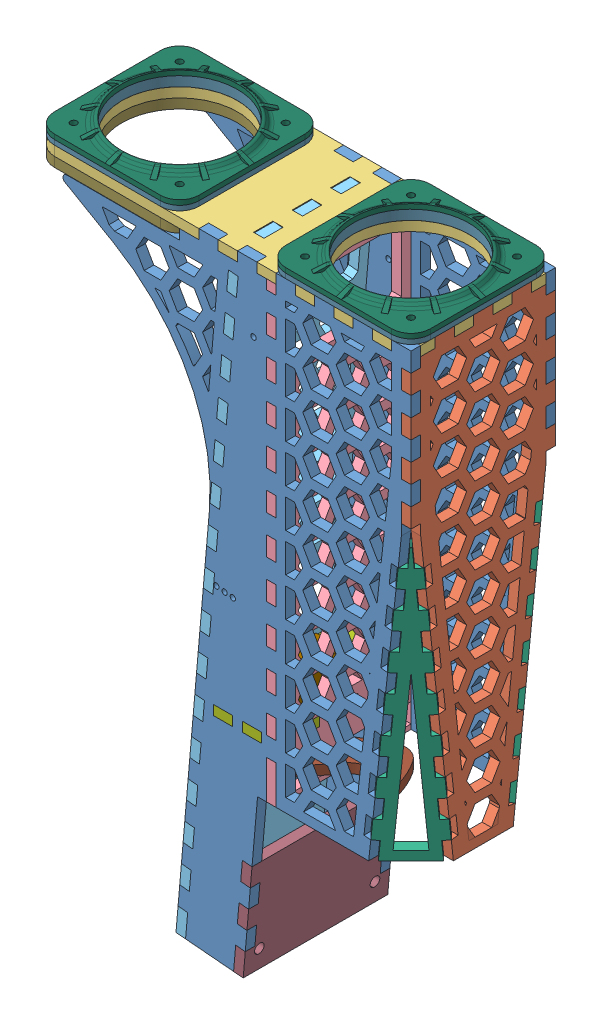
SolidWorks assembly Dispenser Assembly, configuration Default. Lengths in mm.
Overall size (257.34 422.48 114.62).
20 component instances, 15 part files, 45 mates.
Components (placement in the parent):
- Dispenser Side-1: Dispenser Side [Default] at (86.2541 40.0661 209.2088) size (229.27 412.41 6.35)
- Dispenser Side-2: Dispenser Side [Default] at (86.2541 40.0661 298.1088) size (229.27 412.41 6.35)
- Dispenser Back-1: Dispenser Back [Default] at (231.9768 40.0661 209.2088) x (0 0 1) z (-1 0 0) size (95.25 304.8 6.35)
- Dispenser Top-1: Dispenser Top [Default] at (231.9768 338.5161 304.4588) x (0 0 -1) z (1 0 0) size (95.25 6.35 247.65)
- Dispenser Inside-1: Dispenser Inside [Default] at (143.0768 40.0661 209.2088) x (0 0 1) z (-1 0 0) size (95.25 304.8 6.35)
- Dispenser Front-1: Dispenser Front [Default] at (92.58 39.5127 209.2088) x (0 0 1) z (-0.996195 0.087156 0) size (95.25 410.65 6.35)
- Dispenser Back Angle-1: Dispenser Back Angle [Default] at (199.6021 40.5578 299.9821) x (0.707107 0 -0.707107) z (0.704984 -0.077432 0.704984) size (37.49 189.58 6.35)
- Dispenser Back Angle-2: Dispenser Back Angle [Default] at (204.0787 40.0661 209.2088) x (0.707107 0 0.707107) z (-0.704984 0.077432 0.704984) size (37.49 189.58 6.35)
- Dispenser Bottom-1: Dispenser Bottom [Default] at (86.2541 40.0661 209.2088) x (0 0 1) z (-1 0 0) size (95.25 6.35 53.49)
- Tetrix Servo 180° (with Horn)-4: Tetrix Servo 180° (with Horn) [Default] at (143.1518 72.543 274.1079) x (-1 0 0) z (0 0 1) size (22 47.52 56.6)
  - Tetrix Servo Body Screw B-1: Tetrix Servo Body Screw B [Default] at (19.125 20.2268 4.9509) size (5.08 10.95 5.08)
  - Tetrix Servo Body B-1: Tetrix Servo Body B [Default] at (19.125 0.7268 4.9509) size (20 43.2 56.6)
  - Tetrix Servo Horn B-1: Tetrix Servo Horn B [Default] at (19.125 18.2268 4.9509) size (22 6.2 22)
- Dispenser Latch-2: Dispenser Latch [Default] at (124.0268 52.3161 279.0588) x (-0.008189 0 -0.999966) z (-0.999966 0 0.008189) size (55.08 6.35 76.2)
- Tube End Plate-3: Tube End Plate [Default] at (31.9518 332.1661 256.8338) x (-1 0 0) z (0 0 -1) size (95.25 6.35 95.25)
- Dispenser Bottom Back-2: Dispenser Bottom Back [Default] at (130.535 36.192 209.2088) x (0 0 1) z (-0.996195 0.087156 0) size (95.25 66.58 6.35)
- Tube Printed Plate A-1: Tube Printed Plate A [Default] at (184.3518 344.8661 256.8338) x (1 0 0) z (0 1 0) size (95.25 95.25 6.35)
- Tube Printed Plate A-2: Tube Printed Plate A [Default] at (31.9518 344.8661 256.8338) x (1 0 0) z (0 1 0) size (95.25 95.25 6.35)
- Tube Printed Plate B-1: Tube Printed Plate B [Default] at (184.3518 344.8661 256.8338) x (1 0 0) z (0 1 0) size (95.25 95.25 6.35)
- Tube Printed Plate B-2: Tube Printed Plate B [Default] at (31.9518 344.8661 256.8338) x (1 0 0) z (0 1 0) size (95.25 95.25 6.35)
Mates (geometry in assembly coordinates):
- Coincident14: coincident aligned: plane of Dispenser Side-1 through (86.2541 40.0661 215.5588) normal (-0.996195 0.087156 0); plane of Dispenser Front-1 through (86.2541 40.0661 209.2088) normal (-0.996195 0.087156 0)
- Coincident22: coincident aligned: plane of Dispenser Side-1 through (86.2541 344.8661 215.5588) normal (0 1 0); plane of Dispenser Side-2 through (86.2541 344.8661 304.4588) normal (0 1 0)
- Coincident55: coincident: plane of Dispenser Top-1 through (231.9768 344.8661 304.4588) normal (0 1 0); line of Dispenser Front-1 through (112.9207 344.8661 263.1838) axis (0 0 -1)
- Distance2: distance = 31.75 mm aligned: plane of Dispenser Bottom-1 through (89.5875 71.8161 304.4588) normal (0 -1 0); plane of Dispenser Side-2 through (86.2541 40.0661 304.4588) normal (0 -1 0)
- Coincident80: coincident anti-aligned: plane of Dispenser Bottom-1 through (89.5875 71.8161 304.4588) normal (0 -1 0); plane of Tetrix Servo 180° (with Horn)-4/Tetrix Servo Body B-1 through (131.9018 71.8161 294.1588) normal (0 1 0)
- Concentric3: concentric aligned: cylinder of Dispenser Bottom-1 through (119.0268 71.8161 293.0588) axis (0 1 0) radius 1.75; cylinder of Tetrix Servo 180° (with Horn)-4/Tetrix Servo Body B-1 through (119.0268 69.3161 293.0588) axis (0 1 0) radius 2.15
- Concentric4: concentric aligned: cylinder of Dispenser Bottom-1 through (129.0268 71.8161 245.0588) axis (0 1 0) radius 1.75; cylinder of Tetrix Servo 180° (with Horn)-4/Tetrix Servo Body B-1 through (129.0268 69.3161 245.0588) axis (0 1 0) radius 2.15
- Concentric6: concentric anti-aligned: cylinder of Tetrix Servo 180° (with Horn)-4/Tetrix Servo Horn B-1 through (124.0268 54.3161 279.0588) axis (0 -1 0) radius 11; cylinder of Dispenser Latch-2 through (124.0268 45.9661 279.0588) axis (0 1 0) radius 3.175
- Coincident81: coincident anti-aligned: plane of Tetrix Servo 180° (with Horn)-4/Tetrix Servo Horn B-1 through (124.0268 52.3161 279.0588) normal (0 -1 0); plane of Dispenser Latch-2 through (124.0268 52.3161 279.0588) normal (0 1 0)
- Coincident85: coincident aligned: plane of Dispenser Side-2 through (86.2541 40.0661 304.4588) normal (0 0 1); plane of Dispenser Front-1 through (86.2541 40.0661 304.4588) normal (0 0 1)
- Coincident86: coincident aligned: plane of Dispenser Side-2 through (86.2541 40.0661 304.4588) normal (0 0 1); plane of Dispenser Top-1 through (231.9768 344.8661 304.4588) normal (0 0 1)
- Coincident87: coincident aligned: plane of Dispenser Side-1 through (86.2541 40.0661 209.2088) normal (0 0 -1); plane of Dispenser Top-1 through (231.9768 344.8661 209.2088) normal (0 0 -1)
- Coincident91: coincident anti-aligned: plane of Dispenser Side-2 through (205.4653 52.6902 298.1088) normal (0.109178 0.994022 0); plane of Dispenser Back Angle-1 through (200.9886 53.1819 299.9821) normal (-0.109178 -0.994022 0)
- Coincident92: coincident aligned: line of Dispenser Side-1 through (205.4653 52.6902 209.2088) axis (-0.109178 -0.994022 0); line of Dispenser Back Angle-2 through (206.8518 65.3143 209.2088) axis (-0.109178 -0.994022 0)
- Coincident94: coincident anti-aligned: plane of Dispenser Top-1 through (231.9768 338.5161 304.4588) normal (0 -1 0); plane of Tube End Plate-3 through (31.9518 338.5161 256.8338) normal (0 1 0)
- Coincident95: coincident aligned: plane of Dispenser Top-1 through (231.9768 344.8661 304.4588) normal (0 0 1); plane of Tube End Plate-3 through (-15.6732 338.5161 304.4588) normal (0 0 1)
- Coincident96: coincident aligned: plane of Dispenser Top-1 through (-15.6732 344.8661 304.4588) normal (-1 0 0); plane of Tube End Plate-3 through (-15.6732 338.5161 209.2088) normal (-1 0 0)
- Coincident97: coincident aligned: plane of Dispenser Side-2 through (231.9768 40.0661 304.4588) normal (1 0 0); plane of Dispenser Back-1 through (231.9768 40.0661 209.2088) normal (1 0 0)
- Coincident98: coincident aligned: plane of Dispenser Side-2 through (86.2541 40.0661 304.4588) normal (0 0 1); plane of Dispenser Back-1 through (225.6268 40.0661 304.4588) normal (0 0 1)
- Coincident99: coincident aligned: plane of Dispenser Side-2 through (86.2541 344.8661 304.4588) normal (0 1 0); plane of Dispenser Back-1 through (225.6268 344.8661 209.2088) normal (0 1 0)
- Coincident100: coincident aligned: plane of Dispenser Back-1 through (231.9768 40.0661 209.2088) normal (1 0 0); plane of Dispenser Top-1 through (231.9768 344.8661 304.4588) normal (1 0 0)
- Coincident103: coincident aligned: plane of Dispenser Side-2 through (86.2541 40.0661 304.4588) normal (0 0 1); plane of Dispenser Bottom-1 through (86.2541 40.0661 304.4588) normal (0 0 1)
- Coincident104: coincident aligned: plane of Dispenser Side-2 through (86.2541 40.0661 304.4588) normal (-0.996195 0.087156 0); plane of Dispenser Front-1 through (86.2541 40.0661 209.2088) normal (-0.996195 0.087156 0)
- Coincident106: coincident anti-aligned: line of Dispenser Back-1 through (231.9768 52.6902 277.9473) axis (0 -0.994022 -0.109178); line of Dispenser Back Angle-1 through (231.9768 52.6902 277.9473) axis (0 0.994022 0.109178)
- Coincident107: coincident aligned: line of Dispenser Back-1 through (231.9768 40.0661 237.1069) axis (0 0.994022 -0.109178); line of Dispenser Back Angle-2 through (231.9768 52.6902 235.7203) axis (0 0.994022 -0.109178)
- Coincident108: coincident anti-aligned: plane of Dispenser Side-1 through (143.0768 319.4661 209.2088) normal (-1 0 0); plane of Dispenser Inside-1 through (143.0768 40.0661 209.2088) normal (1 0 0)
- Coincident109: coincident aligned: plane of Dispenser Side-1 through (86.2541 40.0661 209.2088) normal (0 0 -1); plane of Dispenser Inside-1 through (136.7268 40.0661 209.2088) normal (0 0 -1)
- Coincident110: coincident aligned: plane of Dispenser Top-1 through (231.9768 344.8661 304.4588) normal (0 1 0); plane of Dispenser Inside-1 through (136.7268 344.8661 209.2088) normal (0 1 0)
- Coincident111: coincident aligned: plane of Dispenser Inside-1 through (143.0768 40.0661 209.2088) normal (1 0 0); plane of Dispenser Bottom-1 through (143.0768 71.8161 304.4588) normal (1 0 0)
- Coincident112: coincident aligned: plane of Dispenser Side-2 through (86.2541 344.8661 304.4588) normal (0 1 0); plane of Dispenser Top-1 through (231.9768 344.8661 304.4588) normal (0 1 0)
- Coincident113: coincident anti-aligned: plane of Dispenser Side-2 through (120.8885 -1.2095 298.1088) normal (0.996195 -0.087156 0); plane of Dispenser Bottom Back-2 through (124.2092 36.7455 209.2088) normal (-0.996195 0.087156 0)
- Coincident114: coincident aligned: plane of Dispenser Side-2 through (86.2541 40.0661 304.4588) normal (0 0 1); plane of Dispenser Bottom Back-2 through (124.2092 36.7455 304.4588) normal (0 0 1)
- Coincident115: coincident aligned: plane of Dispenser Side-2 through (77.1303 -64.2193 298.1088) normal (-0.087156 -0.996195 0); plane of Dispenser Bottom Back-2 through (121.4112 -68.0934 209.2088) normal (-0.087156 -0.996195 0)
- Coincident116: coincident anti-aligned: plane of Dispenser Top-1 through (231.9768 344.8661 304.4588) normal (0 1 0); plane of Tube Printed Plate A-1 through (184.3518 344.8661 256.8338) normal (0 -1 0)
- Coincident117: coincident anti-aligned: plane of Dispenser Top-1 through (231.9768 344.8661 304.4588) normal (0 1 0); plane of Tube Printed Plate A-2 through (31.9518 344.8661 256.8338) normal (0 -1 0)
- Coincident118: coincident aligned: plane of Dispenser Side-2 through (86.2541 40.0661 304.4588) normal (0 0 1); plane of Tube Printed Plate A-2 through (79.5768 348.0411 304.4588) normal (0 0 1)
- Coincident119: coincident aligned: plane of Dispenser Side-2 through (86.2541 40.0661 304.4588) normal (0 0 1); plane of Tube Printed Plate A-1 through (231.9768 348.0411 304.4588) normal (0 0 1)
- Concentric7: concentric anti-aligned: cylinder of Dispenser Top-1 through (184.3518 338.5161 256.8338) axis (0 1 0) radius 38.1; cylinder of Tube Printed Plate A-1 through (184.3518 348.0411 256.8338) axis (0 -1 0) radius 38.1
- Concentric8: concentric anti-aligned: cylinder of Dispenser Top-1 through (31.9518 338.5161 256.8338) axis (0 1 0) radius 38.1; cylinder of Tube Printed Plate A-2 through (31.9518 348.0411 256.8338) axis (0 -1 0) radius 38.1
- Coincident121: coincident aligned: plane of Tube Printed Plate A-1 through (231.9768 348.0411 304.4588) normal (0 0 1); plane of Tube Printed Plate B-1 through (231.9768 348.0411 304.4588) normal (0 0 1)
- Concentric9: concentric aligned: cylinder of Tube Printed Plate A-1 through (184.3518 348.0411 256.8338) axis (0 -1 0) radius 38.1; cylinder of Tube Printed Plate B-1 through (184.3518 348.0411 256.8338) axis (0 -1 0) radius 38.1
- Coincident123: coincident aligned: plane of Tube Printed Plate A-2 through (79.5768 348.0411 304.4588) normal (0 0 1); plane of Tube Printed Plate B-2 through (79.5768 348.0411 304.4588) normal (0 0 1)
- Concentric10: concentric aligned: cylinder of Tube Printed Plate A-2 through (31.9518 348.0411 256.8338) axis (0 -1 0) radius 38.1; cylinder of Tube Printed Plate B-2 through (31.9518 348.0411 256.8338) axis (0 -1 0) radius 38.1
- Coincident124: coincident anti-aligned: plane of Tube Printed Plate A-2 through (31.9518 348.0411 256.8338) normal (0 1 0); plane of Tube Printed Plate B-2 through (31.9518 348.0411 256.8338) normal (0 -1 0)
- Coincident125: coincident anti-aligned: plane of Tube Printed Plate A-1 through (184.3518 348.0411 256.8338) normal (0 1 0); plane of Tube Printed Plate B-1 through (184.3518 348.0411 256.8338) normal (0 -1 0)
